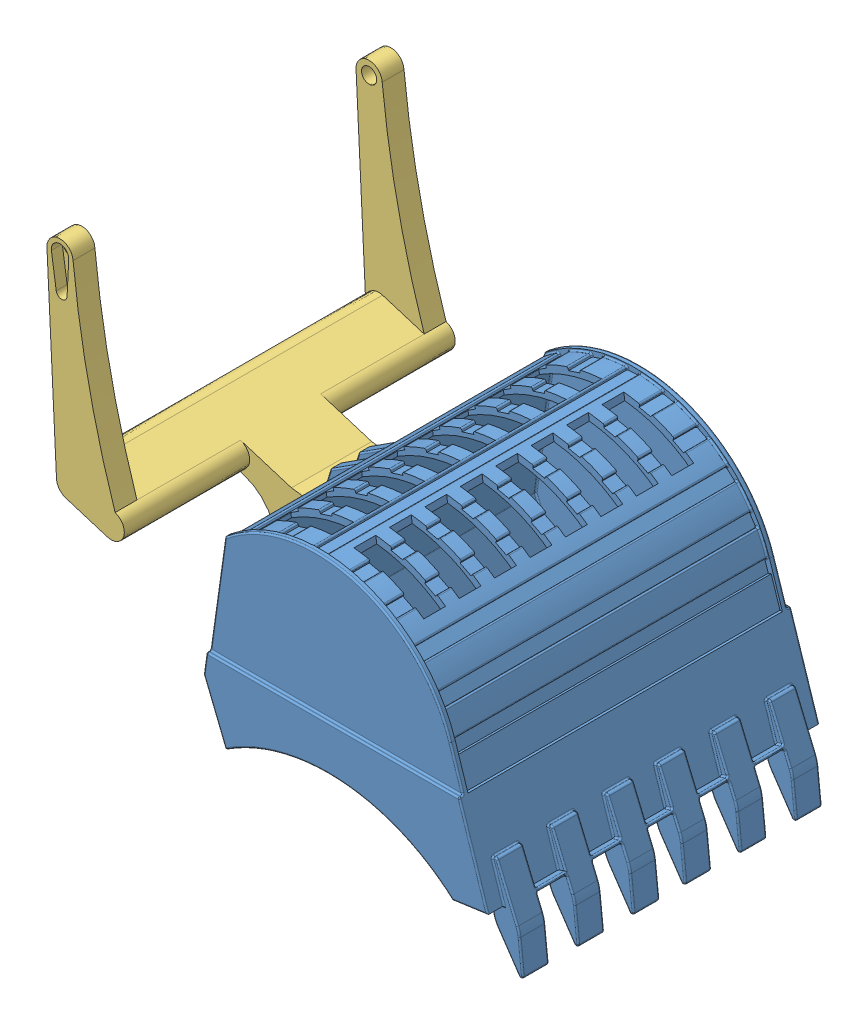
SolidWorks assembly Bucket_With_Connector, configuration Default. Lengths in mm.
Overall size (229.43 196.08 152.19).
3 component instances, 3 part files, 5 mates.
Components (placement in the parent):
- 5. Bucket-1: 5. Bucket [Default] at origin size (155.75 128.07 152.19)
- Bucket_Connector-3: Bucket_Connector [Default] at (766.966 72.6433 -3.7628) x (0.125408 0.992105 0) z (0 0 1) size (57.64 24.31 7.5)
- Collector_Arm-1: Collector_Arm [Default] at (766.966 72.6433 -18.3778) x (0.125408 0.992105 0) z (0 0 1) size (154.09 86.94 151.7)
Mates (geometry in assembly coordinates):
- Concentric1: concentric aligned: cylinder of 5. Bucket-1 through (772.6897 117.923 9.1872) axis (0 0 -1) radius 4.025; cylinder of Bucket_Connector-3 through (772.6897 117.923 3.7372) axis (0 0 -1) radius 4.025
- Coincident1: coincident anti-aligned: plane of 5. Bucket-1 through (777.755 98.6381 -3.7628) normal (0 0 1); plane of Bucket_Connector-3 through (766.966 72.6433 -3.7628) normal (0 0 -1)
- Concentric2: concentric aligned: cylinder of 5. Bucket-1 through (766.966 72.6433 27.2297) axis (0 0 -1) radius 3.8733; cylinder of Collector_Arm-1 through (766.966 72.6433 18.3822) axis (0 0 -1) radius 4.025
- Concentric3: concentric aligned: cylinder of 5. Bucket-1 through (772.6897 117.923 9.1872) axis (0 0 -1) radius 4.025; cylinder of Collector_Arm-1 through (772.6897 117.923 18.3822) axis (0 0 -1) radius 4.025
- Coincident3: coincident anti-aligned: plane of 5. Bucket-1 through (777.755 98.6381 -9.1878) normal (0 0 -1); plane of Collector_Arm-1 through (766.966 72.6433 -9.1878) normal (0 0 1)
